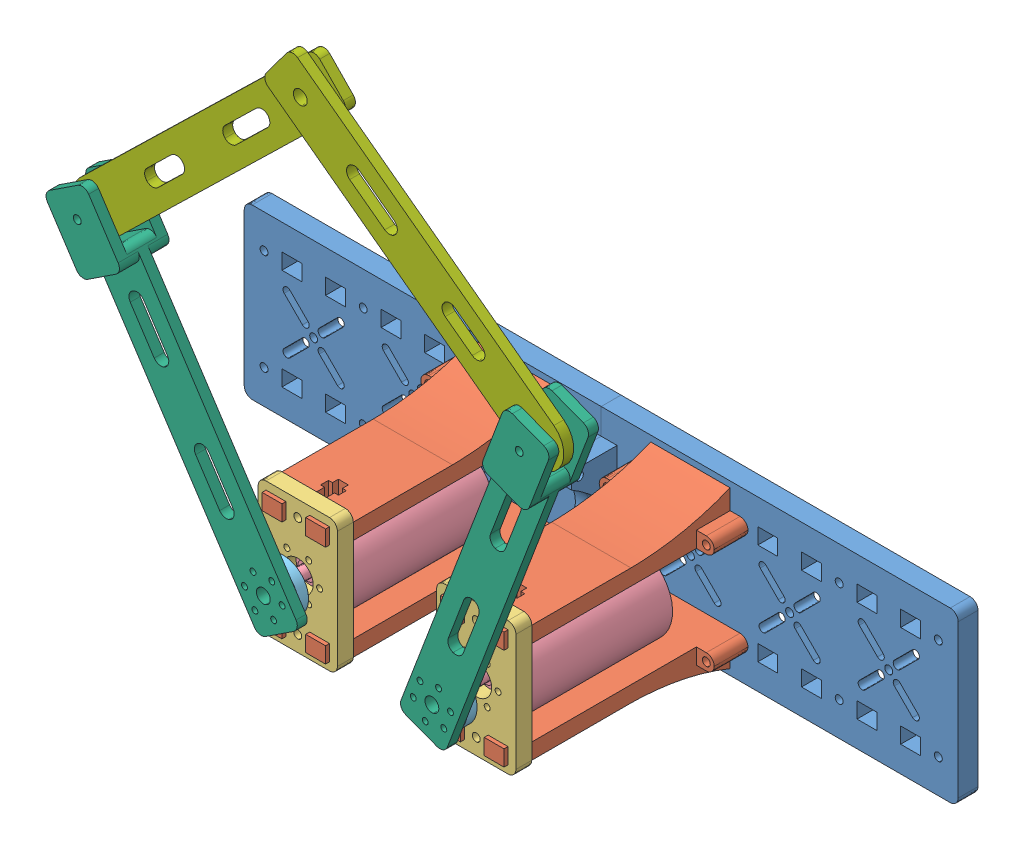
SolidWorks assembly Assem1, configuration Default. Lengths in mm.
Overall size (360 293.97 150.38).
16 component instances, 7 part files, 42 mates.
Components (placement in the parent):
- base-1: base [Varsayılan] at (-73.2618 -233.9487 88.7562) size (180 85 33)
- base-2: base [Varsayılan] at (-253.2618 -233.9487 88.7562) x (-1 0 0) z (0 0 1) size (180 85 33)
- support-1: support [Default] at (-118.2618 -204.4487 148.7575) x (0 0 -1) z (0 -1 0) size (120 58 18)
- support-2: support [Default] at (-118.2618 -263.4487 148.7575) x (0 0 -1) z (0 1 0) size (120 58 18)
- motor_base-1: motor_base [Default] at (-118.2618 -233.9487 198.7575) size (40 67 8)
- maxon_148877-1: maxon_148877 [Default] at (-118.2618 -233.9487 127.7575) x (0.5 -0.866025 0) z (-0.866025 -0.5 0) size (40 91.3 40)
- Wheel Hub-1: Wheel Hub [Default] at (-118.2618 -233.9487 224.1375) x (-0.935074 0.354454 0) z (0 0 -1) size (25.4 25.4 9.21)
- handle-1: handle [Varsayılan] at (-109.5691 -175.7513 226.6375) x (0 0 -1) z (0.935074 -0.354454 0) size (25 180 25)
- handle1-2: handle1 [Default] at (-126.4195 -45.1338 224.1375) x (-0.802734 0.596337 0) z (0 0 1) size (177.5 25 5)
- support-3: support [Default] at (-208.2618 -263.4487 148.7575) x (0 0 -1) z (0 1 0) size (120 58 18)
- support-4: support [Default] at (-208.2618 -204.4487 148.7575) x (0 0 -1) z (0 -1 0) size (120 58 18)
- motor_base-2: motor_base [Default] at (-208.2618 -233.9487 198.7575) size (40 67 8)
- handle-2: handle [Varsayılan] at (-250.3084 -192.7833 221.6375) x (0 0 -1) z (0.835405 0.549635 0) size (25 180 25)
- maxon_148877-2: maxon_148877 [Default] at (-208.2618 -233.9487 127.7575) x (1 0 0) z (0 -1 0) size (40 91.3 40)
- Wheel Hub-2: Wheel Hub [Default] at (-208.2618 -233.9487 219.1375) x (-0.835405 -0.549635 0) z (0 0 -1) size (25.4 25.4 9.21)
- handle1-3: handle1 [Default] at (-236.5584 -52.4802 219.1375) x (0.716422 0.697667 0) z (0 0 1) size (177.5 25 5)
Mates (geometry in assembly coordinates):
- Concentric1: concentric: circle of base-1; circle of base-2
- Coincident3: coincident: plane of base-1 through (-73.2618 -233.9487 98.7562) normal (0 0 1); plane of base-2 through (-253.2618 -233.9487 98.7562) normal (0 0 1)
- Coincident4: coincident: plane of base-1 through (-163.2618 -276.4487 98.7562) normal (-1 0 0); plane of base-2 through (-163.2618 -191.4487 98.7562) normal (1 0 0)
- Concentric2: concentric: circle of base-1; circle of support-1
- Concentric3: concentric: circle of base-1; circle of support-1
- Coincident5: coincident: plane of base-1 through (-73.2618 -233.9487 98.7562) normal (0 0 1); plane of support-1 through (-98.2618 -204.4487 98.7562) normal (0 0 -1)
- Concentric4: concentric: circle of base-1; circle of support-2
- Concentric5: concentric: circle of base-1; circle of support-2
- Coincident6: coincident: plane of base-1 through (-73.2618 -233.9487 98.7562) normal (0 0 1); plane of support-2 through (-138.2618 -263.4487 98.7562) normal (0 0 -1)
- Coincident7: coincident: plane of support-2 through (-134.2618 -255.4487 148.7575) normal (-1 0 0); plane of motor_base-1 through (-134.2618 -255.4487 206.7575) normal (1 0 0)
- Coincident8: coincident: plane of support-2 through (-118.2618 -263.4487 148.7575) normal (0 -1 0); plane of motor_base-1 through (-134.2618 -263.4487 206.7575) normal (0 1 0)
- Coincident10: coincident: plane of support-2 through (-118.2618 -255.4487 198.7575) normal (0 0 1); plane of motor_base-1 through (-102.2618 -263.4487 198.7575) normal (0 0 -1)
- Concentric6: concentric: circle of motor_base-1; circle of maxon_148877-1
- Concentric7: concentric: circle of motor_base-1; circle of maxon_148877-1
- Coincident11: coincident: plane of motor_base-1 through (-102.2618 -263.4487 198.7575) normal (0 0 -1); plane of maxon_148877-1 through (-118.2618 -233.9487 198.7575) normal (0 0 1)
- Concentric8: concentric: circle of maxon_148877-1; circle of Wheel Hub-1
- Coincident13: coincident: plane of Wheel Hub-1 through (-118.2618 -233.9487 224.1375) normal (0 0 1); plane of handle-1 through (-111.8902 -252.4054 224.1375) normal (0 0 -1)
- Concentric9: concentric: circle of Wheel Hub-1; circle of handle-1
- Concentric10: concentric: circle of Wheel Hub-1; circle of handle-1
- Concentric12: concentric: circle of handle-1; circle of handle1-2
- Distance2: distance = 5 mm: plane of handle1-2 through (-64.2076 -91.35 229.1375) normal (0 0 1); plane of handle-1 through (-48.0885 -84.0922 234.1375) normal (0 0 -1)
- Concentric13: concentric: circle of base-2; circle of support-3
- Concentric14: concentric: circle of base-2; circle of support-3
- Coincident16: coincident: plane of base-2 through (-253.2618 -233.9487 98.7562) normal (0 0 1); plane of support-3 through (-228.2618 -263.4487 98.7562) normal (0 0 -1)
- Concentric16: concentric: circle of base-2; circle of support-4
- Concentric17: concentric: circle of base-2; circle of support-4
- Coincident18: coincident: plane of base-2 through (-253.2618 -233.9487 98.7562) normal (0 0 1); plane of support-4 through (-188.2618 -204.4487 98.7562) normal (0 0 -1)
- Coincident19: coincident: plane of support-3 through (-214.2618 -255.4487 148.7575) normal (1 0 0); plane of motor_base-2 through (-214.2618 -255.4487 206.7575) normal (-1 0 0)
- Coincident20: coincident: plane of support-3 through (-208.2618 -263.4487 148.7575) normal (0 -1 0); plane of motor_base-2 through (-224.2618 -263.4487 206.7575) normal (0 1 0)
- Coincident21: coincident: plane of support-3 through (-208.2618 -255.4487 198.7575) normal (0 0 1); plane of motor_base-2 through (-192.2618 -263.4487 198.7575) normal (0 0 -1)
- Concentric18: concentric: circle of motor_base-2; circle of maxon_148877-2
- Concentric19: concentric: circle of motor_base-2; circle of maxon_148877-2
- Coincident23: coincident: plane of motor_base-2 through (-192.2618 -263.4487 198.7575) normal (0 0 -1); plane of maxon_148877-2 through (-208.2618 -233.9487 198.7575) normal (0 0 1)
- Concentric20: concentric: circle of maxon_148877-2; circle of Wheel Hub-2
- Distance3: distance = 5 mm: plane of Wheel Hub-2 through (-208.2618 -233.9487 219.1375) normal (0 0 1); plane of handle-1 through (-111.8902 -252.4054 224.1375) normal (0 0 -1)
- Coincident25: coincident: plane of maxon_148877-1 through (-118.2618 -233.9487 219.0575) normal (0 0 1); plane of Wheel Hub-1 through (-118.2618 -233.9487 219.0575) normal (0 0 -1)
- Concentric21: concentric: circle of handle-2; circle of Wheel Hub-2
- Concentric22: concentric: circle of handle-2; circle of Wheel Hub-2
- Coincident27: coincident: plane of handle-2 through (-189.5747 -239.6093 219.1375) normal (0 0 -1); plane of Wheel Hub-2 through (-208.2618 -233.9487 219.1375) normal (0 0 1)
- Concentric23: concentric: circle of handle-2; circle of handle1-3
- Distance4: distance = 5 mm: plane of handle-2 through (-288.509 -89.2364 229.1375) normal (0 0 -1); plane of handle1-3 through (-292.0811 -106.5494 224.1375) normal (0 0 1)
- Concentric24: concentric: circle of handle1-2; circle of handle1-3
